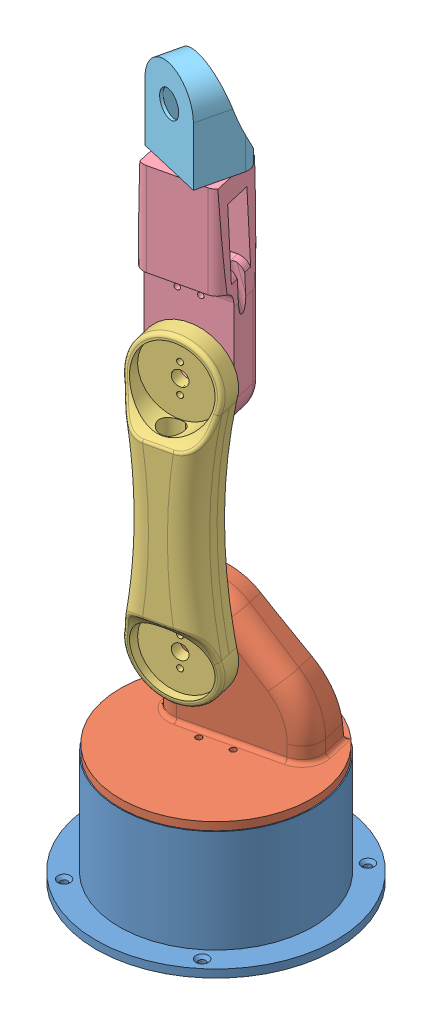
SolidWorks assembly Link_Assembly, configuration Default. Lengths in mm.
Overall size (121.5 352.03 121.5).
5 component instances, 5 part files, 6 mates.
Components (placement in the parent):
- Base-1: Base [Default] at (-27.3346 0 -18.7512) x (1 0 0) z (0 1 0) size (121.5 121.5 56)
- Waist-1: Waist [Default] at (-27.3346 56 -18.7512) x (-0.224191 0 -0.974545) z (0.974545 0 -0.224191) size (97 73.59 97)
- Arm 01-1: Arm 01 [Default] at (-37.0793 96.28 0.9346) x (-0.974545 0 0.224191) z (-0.224191 0 -0.974545) size (42.06 162.08 21.01)
- Arm 02-1: Arm 02 [Default] at (-41.7873 251.03 -19.5309) x (0 1 0) z (-0.224191 0 -0.974545) size (115 38 27)
- Arm 03-1: Arm 03 [Default] at (-42.7221 306.03 -27.2254) x (-0.973364 0 -0.229265) z (0.229265 0 -0.973364) size (33.02 46 28)
Mates (geometry in assembly coordinates):
- ProfileCenter1: profile center = 0 mm aligned: plane of Waist-1 through (-27.3346 56 -18.7512) normal (0 -1 0); plane of Base-1 through (-27.3346 56 -18.7512) normal (0 1 0)
- ProfileCenter2: profile center = 0 mm aligned: circle of Arm 02-1; circle of Arm 01-1
- ProfileCenter3: profile center = 0 mm aligned: circle of Arm 03-1; circle of Arm 02-1
- ProfileCenter4: profile center = 0 mm anti-aligned: circle of Waist-1; circle of Arm 01-1
- LimitAngle3: limit planar angle = 1.570796 rad aligned: plane of Waist-1 through (-27.3346 56 -18.7512) normal (0 1 0); plane of Arm 02-1 through (-37.0793 96.28 0.9346) normal (-0.974545 0 0.224191); unknown of Arm 01-1
- LimitAngle4: limit planar angle = 1.570796 rad anti-aligned: plane of Arm 01-1 through (-37.0793 96.28 0.9346) normal (0 1 0); plane of Arm 02-1 through (-41.7873 251.03 -19.5309) normal (0.974545 0 -0.224191)
